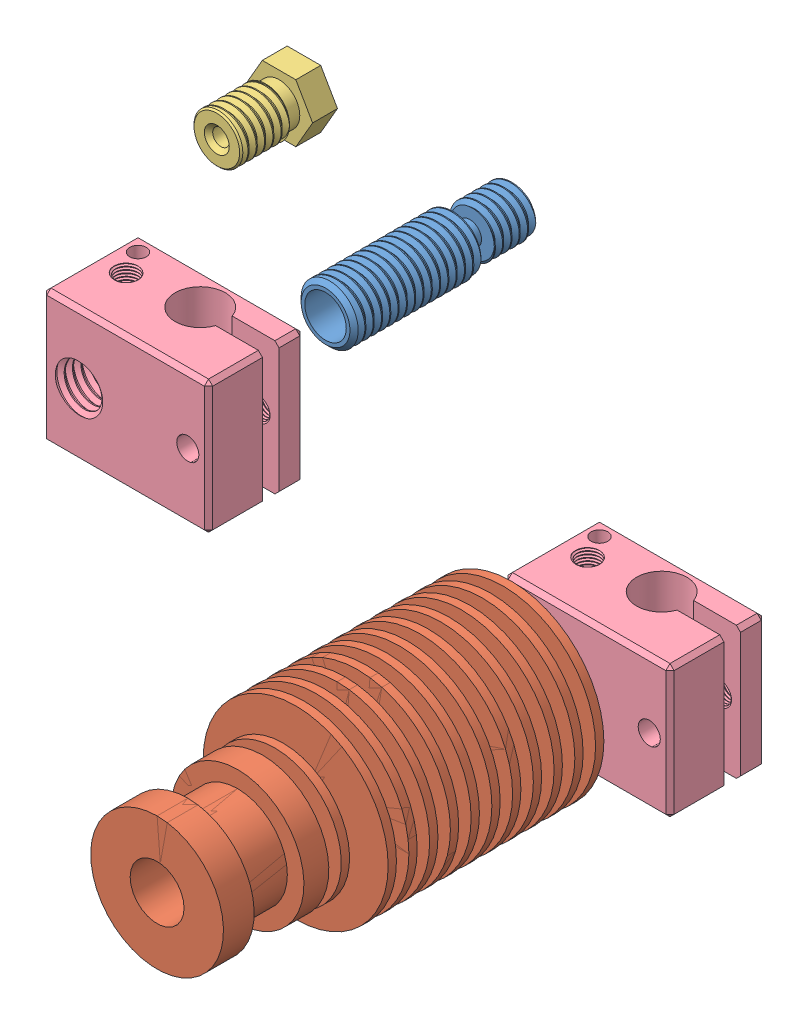
SolidWorks assembly e3d_v6_175.stp, configuration Default. Lengths in mm.
Overall size (60.5 64.65 62.82).
10 component instances, 4 part files, 0 mates.
Components (placement in the parent):
- Single parts.stp-1: Single parts.stp [Default] at origin size (56.15 64.65 44.7)
  - Heatbreak.stp-1: Heatbreak.stp [Default] at origin size (7.03 7.04 22.45)
  - Heatsink.stp-1: Heatsink.stp [Default] at origin size (22.3 22.3 42.75)
  - Nozzle 0.4mm.stp-1: Nozzle 0.4mm.stp [Default] at origin size (8.08 7 12.54)
  - Heaterblock.stp-1: Heaterblock.stp [Default] at origin size (20 16.05 11.6)
- Assembly.stp-1: Assembly.stp [Default] at origin size (26.65 22.3 62.82)
  - Heatbreak.stp-1: Heatbreak.stp [Default] at (0 -50 -7.6178) size (7.03 7.04 22.45)
  - Heaterblock.stp-1: Heaterblock.stp [Default] at (40.5 -17 -15.1177) size (20 16.05 11.6)
  - Nozzle 0.4mm.stp-1: Nozzle 0.4mm.stp [Default] at (25 -50 -18.1177) size (8.08 7 12.54)
  - Heatsink.stp-1: Heatsink.stp [Default] at origin size (22.3 22.3 42.75)
